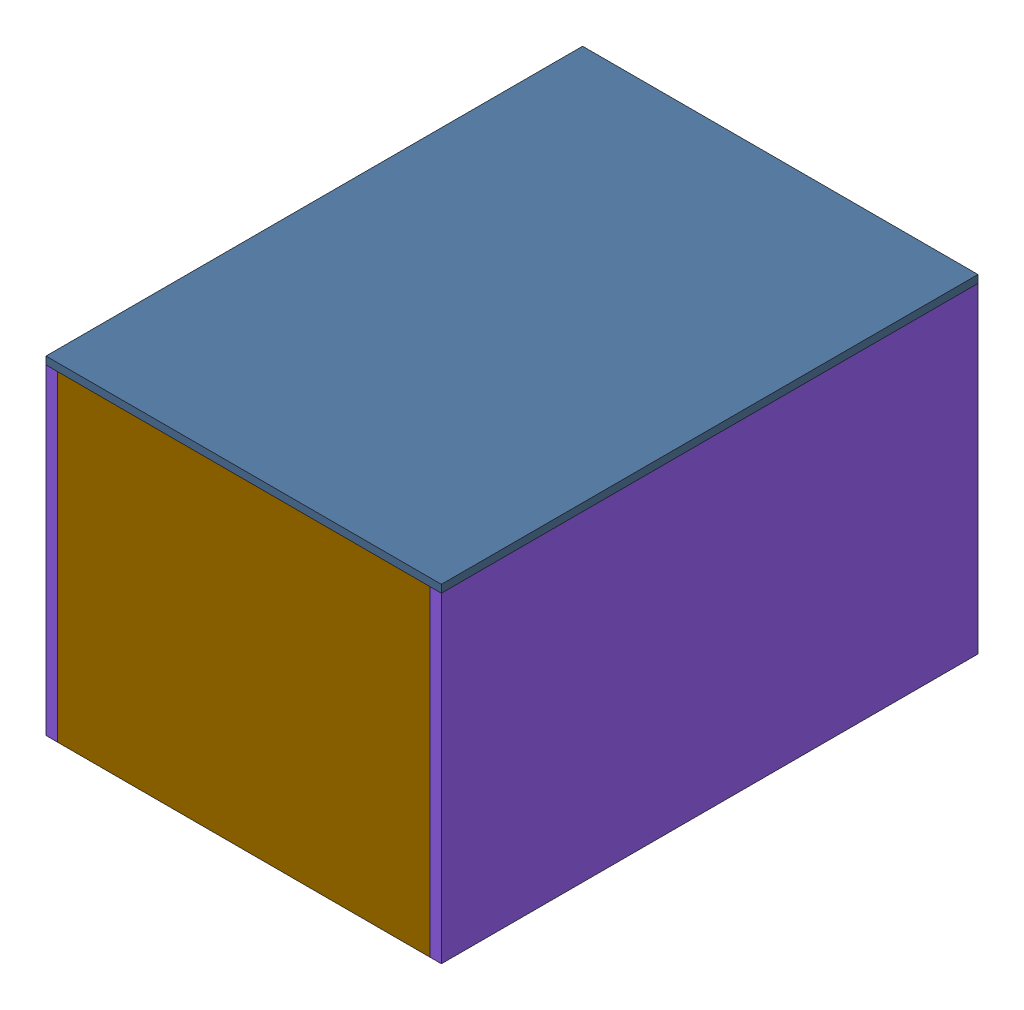
SolidWorks assembly assembly, configuration Default. Lengths in mm.
Overall size (308 256 418).
78 component instances, 28 part files, 32 mates.
Components (placement in the parent):
- base-1: base [Default] at (-177.5047 -28.3355 199.9504) size (290 9 400)
- motor_mount-1: motor_mount [Default] at (-11.0047 -19.3355 -200.0496) x (-1 0 0) z (0 1 0) size (75 48 43)
- distancer-1: distancer [Default] at (-107.8858 -19.3355 185.9504) size (9.24 40 8)
- distancer-2: distancer [Default] at (42.1142 -19.3355 185.9504) size (9.24 40 8)
- distancer-3: distancer [Default] at (-107.8858 -19.3355 -124.0496) size (9.24 40 8)
- distancer-4: distancer [Default] at (42.1142 -19.3355 -124.0496) size (9.24 40 8)
- nema_17_short-1: nema_17_short [Default] at (-53.5047 -18.8355 -197.1189) x (1 0 0) z (0 -1 0) size (42 57 42)
- Assem1-1: Assem1 [Default] at (67.4953 20.6645 194.9504) x (0 0 -1) z (1 0 0) size (330 12.5 200)
  - table-1: table [Default] at origin size (330 6 200)
  - Part1-1: Part1 [Default] at (0 6 0) x (1 0 0) z (0 1 0) size (330 95 6.5)
- Part1-1: Part1 [Default] at (-132.5047 26.6645 -135.0496) x (0 0 1) z (0 1 0) size (330 95 6.5)
- moving assembly-1: moving assembly [Default] at (160.3073 -54.8798 28.3581) x (1 0 0) z (0 1 0) size (280 330 218.5)
  - bar_and_mounts-1: bar_and_mounts [Default] at (-49.2169 -149.0461 22.6055) size (55 330 19)
    - bar_mount-1: bar_mount [Default] at (-61.595 -12.5462 12.9389) size (55 12 19)
    - bar_mount-2: bar_mount [Default] at (-61.595 295.4538 12.9389) size (55 12 19)
    - bar-1: bar [Default] at (-29.595 -17.5462 23.9389) size (8 330 8)
  - bar_and_mounts_switch-1: bar_and_mounts_switch [Default] at (-356.8295 169.2155 27.6951) x (-1 0 0) z (0 0 1) size (55 330 24.7)
    - bar_mount_switch-1: bar_mount_switch [Default] at (-82.0176 10.8078 7.8492) size (55 12 19)
    - bar-1: bar [Default] at (-50.0176 5.8078 18.8492) size (8 330 8)
    - bar_mount-1: bar_mount [Default] at (-82.0176 318.8078 7.8492) size (55 12 19)
    - switch-1: switch [Default] at (-54.8176 17.8078 26.8492) x (1 0 0) z (0 -1 0) size (12.8 5.7 10.85)
  - pusher_bearing_mount-1: pusher_bearing_mount [Default] at (-93.535 -18.6939 68.5444) size (40 50 27.5)
  - pusher_bearing_mount-2: pusher_bearing_mount [Default] at (-321.535 -18.6939 68.5444) size (40 50 27.5)
  - lm8uul-1: lm8uul [Default] at (-78.8119 -15.6939 46.5444) size (15 45 15)
  - lm8uul-2: lm8uul [Default] at (-306.8119 -15.6939 46.5444) size (15 45 15)
  - pusher_plank-1: pusher_plank [Default] at (-332.8119 -18.6939 68.5444) x (1 0 0) z (0 -1 0) size (280 6.5 50)
  - pusher_mount-1: pusher_mount [Default] at (-192.8119 -8.6939 68.5444) size (40 25 20.5)
  - socket head cap screw_din-2: socket head cap screw_din [DIN 912 M3 x 16 --- 16N] at (-89.8119 152.4077 57.5444) x (0 0 -1) z (1 0 0) size (19 5.5 5.5)
  - socket head cap screw_din-3: socket head cap screw_din [DIN 912 M3 x 16 --- 16N] at (-295.8119 152.4077 57.5444) x (0 0 -1) z (1 0 0) size (19 5.5 5.5)
  - socket head cap screw_din-4: socket head cap screw_din [DIN 912 M3 x 16 --- 16N] at (-295.8119 -155.5923 57.5444) x (0 0 -1) z (1 0 0) size (19 5.5 5.5)
  - socket head cap screw_din-5: socket head cap screw_din [DIN 912 M3 x 16 --- 16N] at (-89.8119 -155.5923 57.5444) x (0 0 -1) z (1 0 0) size (19 5.5 5.5)
  - slotted pan head screw_din-1: slotted pan head screw_din [ISO 1580 - M1.6 x 8 --- 8N] at (-311.6619 150.4077 61.2444) x (0 0 -1) z (1 0 0) size (9.03 3.2 3.2)
  - slotted pan head screw_din-4: slotted pan head screw_din [ISO 1580 - M1.6 x 8 --- 8N] at (-305.1619 150.4077 61.2444) x (0 0 -1) z (1 0 0) size (9.03 3.2 3.2)
  - slotted pan head screw_din-8: slotted pan head screw_din [ISO 1580 - M4 x 10 --- 10N] at (-207.5619 11.3061 61.1444) x (0 0 1) z (-1 0 0) size (12.47 8 8)
  - slotted pan head screw_din-9: slotted pan head screw_din [ISO 1580 - M4 x 10 --- 10N] at (-178.0619 3.8061 61.1444) x (0 0 1) z (-1 0 0) size (12.47 8 8)
  - slotted pan head screw_din-10: slotted pan head screw_din [ISO 1580 - M4 x 10 --- 10N] at (-207.5619 -3.6939 61.1444) x (0 0 1) z (-1 0 0) size (12.47 8 8)
  - prevailing torque nut style 1 insert_din-1: prevailing torque nut style 1 insert_din [DIN EN ISO 7040 - M3 - N] at (-89.8119 152.4077 41.3944) x (0.923728 0.383049 0) z (0 0 -1) size (5.5 6.35 4.5)
  - prevailing torque nut style 1 insert_din-2: prevailing torque nut style 1 insert_din [DIN EN ISO 7040 - M3 - N] at (-89.8119 -155.5923 41.3944) x (0.923728 0.383049 0) z (0 0 -1) size (5.5 6.35 4.5)
  - prevailing torque nut style 1 insert_din-3: prevailing torque nut style 1 insert_din [DIN EN ISO 7040 - M3 - N] at (-295.8119 -155.5923 41.3944) x (0.923728 0.383049 0) z (0 0 -1) size (5.5 6.35 4.5)
  - prevailing torque nut style 1 insert_din-4: prevailing torque nut style 1 insert_din [DIN EN ISO 7040 - M3 - N] at (-295.8119 152.4077 41.3944) x (-0.923728 -0.383049 0) z (0 0 -1) size (5.5 6.35 4.5)
  - toothed lock washer 1_din-1: toothed lock washer 1_din [DIN 6797-A3.2] at (-295.8119 152.4077 54.1444) x (0 0 -1) z (1 0 0) size (0.4 5.93 6)
  - toothed lock washer 1_din-2: toothed lock washer 1_din [DIN 6797-A3.2] at (-89.8119 152.4077 54.1444) x (0 0 -1) z (1 0 0) size (0.4 5.93 6)
  - toothed lock washer 1_din-3: toothed lock washer 1_din [DIN 6797-A3.2] at (-89.8119 -155.5923 54.1444) x (0 0 -1) z (1 0 0) size (0.4 5.93 6)
  - toothed lock washer 1_din-4: toothed lock washer 1_din [DIN 6797-A3.2] at (-295.8119 -155.5923 54.9444) x (0 0 1) z (-1 0 0) size (0.4 5.93 6)
  - plain washer 6902 type abc_din-2: plain washer 6902 type abc_din [DIN 6902-A3.6] at (-207.5619 -3.6939 63.5444) x (0 0 1) z (-1 0 0) size (0.8 9 9)
  - plain washer 6902 type abc_din-3: plain washer 6902 type abc_din [DIN 6902-A3.6] at (-207.5619 11.3061 63.5444) x (0 0 1) z (-1 0 0) size (0.8 9 9)
  - plain washer 6902 type abc_din-4: plain washer 6902 type abc_din [DIN 6902-A3.6] at (-178.0619 3.8061 63.5444) x (0 0 1) z (-1 0 0) size (0.8 9 9)
  - hex nut gradec_din-1: hex nut gradec_din [Hexagon Nut ISO 4034 - M8 - N] at (-192.8119 7.7061 57.0444) x (1 0 0) z (0 1 0) size (13 15.01 7.9)
  - plain washer 6902 type abc_din-5: plain washer 6902 type abc_din [DIN 6902-A3.6] at (-321.5619 6.3061 62.7444) x (0 0 1) z (-1 0 0) size (0.8 9 9)
  - plain washer 6902 type abc_din-6: plain washer 6902 type abc_din [DIN 6902-A3.6] at (-292.0619 -12.6939 63.5444) x (0 0 -1) z (1 0 0) size (0.8 9 9)
  - plain washer 6902 type abc_din-7: plain washer 6902 type abc_din [DIN 6902-A3.6] at (-292.0619 25.3061 63.5444) x (0 0 -1) z (1 0 0) size (0.8 9 9)
  - plain washer 6902 type abc_din-8: plain washer 6902 type abc_din [DIN 6902-A3.6] at (-64.0134 -12.6939 63.5444) x (0 0 -1) z (1 0 0) size (0.8 9 9)
  - plain washer 6902 type abc_din-9: plain washer 6902 type abc_din [DIN 6902-A3.6] at (-93.5619 6.3061 63.5444) x (0 0 -1) z (1 0 0) size (0.8 9 9)
  - plain washer 6902 type abc_din-10: plain washer 6902 type abc_din [DIN 6902-A3.6] at (-64.0134 25.3061 63.5444) x (0 0 -1) z (1 0 0) size (0.8 9 9)
  - toothed lock washer 1_din-5: toothed lock washer 1_din [DIN 6797-A4.3] at (-93.5619 6.3061 62.2444) x (0 0 -1) z (1 0 0) size (0.5 7.91 7.91)
  - toothed lock washer 1_din-6: toothed lock washer 1_din [DIN 6797-A4.3] at (-64.0134 -12.6939 62.2444) x (0 0 -1) z (1 0 0) size (0.5 7.91 7.91)
  - toothed lock washer 1_din-7: toothed lock washer 1_din [DIN 6797-A4.3] at (-64.0134 25.3061 62.2444) x (0 0 -1) z (1 0 0) size (0.5 7.91 7.91)
  - toothed lock washer 1_din-8: toothed lock washer 1_din [DIN 6797-A4.3] at (-292.0619 -12.6939 62.2444) x (0 0 -1) z (1 0 0) size (0.5 7.91 7.91)
  - toothed lock washer 1_din-9: toothed lock washer 1_din [DIN 6797-A4.3] at (-292.0619 25.3061 62.2444) x (0 0 -1) z (1 0 0) size (0.5 7.91 7.91)
  - toothed lock washer 1_din-11: toothed lock washer 1_din [DIN 6797-A4.3] at (-321.5619 6.3061 62.2444) x (0 0 -1) z (1 0 0) size (0.5 7.91 7.91)
  - slotted pan head screw_din-11: slotted pan head screw_din [ISO 1580 - M4 x 12 --- 12N] at (-93.5619 6.3061 59.8444) x (0 0 1) z (-1 0 0) size (14.47 8 8)
  - slotted pan head screw_din-12: slotted pan head screw_din [ISO 1580 - M4 x 12 --- 12N] at (-64.0134 25.3061 59.8444) x (0 0 1) z (-1 0 0) size (14.47 8 8)
  - slotted pan head screw_din-13: slotted pan head screw_din [ISO 1580 - M4 x 12 --- 12N] at (-64.0134 -12.6939 59.8444) x (0 0 1) z (-1 0 0) size (14.47 8 8)
  - slotted pan head screw_din-14: slotted pan head screw_din [ISO 1580 - M4 x 12 --- 12N] at (-321.5619 6.3061 59.8444) x (0 0 1) z (-1 0 0) size (14.47 8 8)
  - slotted pan head screw_din-15: slotted pan head screw_din [ISO 1580 - M4 x 12 --- 12N] at (-292.0619 25.3061 59.8444) x (0 0 1) z (-1 0 0) size (14.47 8 8)
  - slotted pan head screw_din-16: slotted pan head screw_din [ISO 1580 - M4 x 12 --- 12N] at (-292.0619 -12.6939 59.8444) x (0 0 1) z (-1 0 0) size (14.47 8 8)
  - carret-1: carret [Default] at (-332.8119 31.3061 75.0444) x (1 0 0) z (0 0 -1) size (280 6.5 120)
  - head_assembly-1: head_assembly [Default] at (-193.7359 2.3231 248.2305) x (1 0 0) z (0 1 0) size (90 120 32)
    - laserhead_base-1: laserhead_base [Default] at (-47.4396 -5.8139 28.9831) size (90 120 8)
    - mount-1: mount [Default] at (-1.9396 79.1861 36.9831) x (0 -1 0) z (-1 0 0) size (32 12 30)
    - calibration-1: calibration [Default] at (-41.9396 28.1861 36.9831) size (50 15 13)
    - calibration-2: calibration [Default] at (-41.9396 83.1861 36.9831) size (50 15 13)
    - mount_top-1: mount_top [Default] at (-31.9396 79.1861 60.9831) x (1 0 0) z (0 1 0) size (30 12 32)
- case_side-1: case_side [Default] at (-186.5047 -28.3355 208.9504) x (0 0 -1) z (1 0 0) size (418 250 9)
- case_back_side-1: case_back_side [Default] at (-177.5047 -28.3355 -209.0496) size (290 250 9)
- case_side-2: case_side [Default] at (112.4953 -28.3355 208.9504) x (0 0 -1) z (1 0 0) size (418 250 9)
- case_back_side-2: case_back_side [Default] at (112.4953 -28.3355 208.9504) x (-1 0 0) z (0 0 -1) size (290 250 9)
- case_top-1: case_top [Default] at (-186.5047 221.6645 -209.0496) x (0 0 1) z (0 1 0) size (418 308 6)
Mates (geometry in assembly coordinates):
- Coincident8: coincident: plane of base-1 through (-177.5047 -19.3355 199.9504) normal (0 1 0); plane of motor_mount-1 through (-11.0047 -19.3355 -200.0496) normal (0 -1 0)
- Coincident12: coincident: plane of base-1 through (-177.5047 -19.3355 199.9504) normal (0 1 0); plane of distancer-1 through (-107.8858 -19.3355 185.9504) normal (0 -1 0)
- Distance9: distance = 10 mm: plane of distancer-1 through (-110.1953 20.6645 189.9504) normal (0 0 1); plane of base-1 through (-177.5047 -19.3355 199.9504) normal (0 0 1)
- Distance10: distance = 65 mm: line of distancer-1 through (-112.5047 20.6645 185.9504) axis (0 -1 0); plane of base-1 through (-177.5047 -19.3355 199.9504) normal (-1 0 0)
- Coincident16: coincident: plane of motor_mount-1 through (-6.0047 23.6645 -157.1189) normal (0 0 -1); plane of nema_17_short-1 through (-14.5047 20.1645 -157.1189) normal (0 0 1)
- Concentric3: concentric: cylinder of motor_mount-1 through (-32.5047 2.1645 -200.0496) axis (0 0 1) radius 11.25; cylinder of nema_17_short-1 through (-32.5047 2.1645 -155.1189) axis (0 0 -1) radius 11
- Distance16: distance = 107.5 mm: plane of motor_mount-1 through (-70.0047 -14.3355 -200.0496) normal (-1 0 0); plane of base-1 through (-177.5047 -19.3355 199.9504) normal (-1 0 0)
- Distance20: distance = 0 mm: plane of motor_mount-1 through (-54.0047 -14.3355 -200.0496) normal (0 0 -1); line of base-1 through (112.4953 -19.3355 -200.0496) axis (-1 0 0)
- Coincident47: coincident: plane of distancer-1 through (-107.8858 20.6645 185.9504) normal (0 1 0); plane of Assem1-1/table-1 through (67.4953 20.6645 194.9504) normal (0 -1 0)
- Distance23: distance = 5 mm: plane of base-1 through (-177.5047 -19.3355 199.9504) normal (0 0 1); plane of Assem1-1/table-1 through (67.4953 26.6645 194.9504) normal (0 0 1)
- Distance24: distance = 45 mm: plane of Assem1-1/table-1 through (67.4953 26.6645 194.9504) normal (1 0 0); plane of base-1 through (112.4953 -19.3355 199.9504) normal (1 0 0)
- Coincident48: coincident: plane of Assem1-1/table-1 through (67.4953 26.6645 194.9504) normal (1 0 0); plane of Part1-1 through (67.4953 33.1645 -135.0496) normal (1 0 0)
- Coincident49: coincident: plane of Assem1-1/table-1 through (67.4953 26.6645 194.9504) normal (0 1 0); plane of Part1-1 through (-132.5047 26.6645 -135.0496) normal (0 -1 0)
- Coincident51: coincident: plane of Assem1-1/table-1 through (67.4953 26.6645 194.9504) normal (0 0 1); plane of Part1-1 through (67.4953 33.1645 194.9504) normal (0 0 1)
- Coincident52: coincident: plane of base-1 through (-177.5047 -19.3355 199.9504) normal (0 1 0); plane of moving assembly-1/bar_and_mounts_switch-1/bar_mount_switch-1 through (-114.5047 -19.3355 -130.0496) normal (0 -1 0)
- Distance25: distance = 8 mm: plane of moving assembly-1/bar_and_mounts_switch-1/bar_mount_switch-1 through (-169.5047 -13.3355 -130.0496) normal (-1 0 0); plane of base-1 through (-177.5047 -19.3355 199.9504) normal (-1 0 0)
- Distance26: distance = 5 mm: plane of moving assembly-1/bar_and_mounts-1/bar_mount-1 through (49.4953 -13.3355 189.9504) normal (0 0 1); plane of Assem1-1/table-1 through (67.4953 26.6645 194.9504) normal (0 0 1)
- Coincident53: coincident: plane of base-1 through (-177.5047 -19.3355 199.9504) normal (-1 0 0); plane of case_side-1 through (-177.5047 -28.3355 208.9504) normal (1 0 0)
- Coincident54: coincident: plane of base-1 through (-177.5047 -28.3355 199.9504) normal (0 -1 0); plane of case_side-1 through (-177.5047 -28.3355 208.9504) normal (0 -1 0)
- Coincident55: coincident: plane of base-1 through (-177.5047 -28.3355 199.9504) normal (0 -1 0); plane of case_back_side-1 through (-177.5047 -28.3355 -200.0496) normal (0 -1 0)
- Coincident56: coincident: plane of base-1 through (-177.5047 -19.3355 -200.0496) normal (0 0 -1); plane of case_back_side-1 through (-177.5047 -28.3355 -200.0496) normal (0 0 1)
- Coincident57: coincident: plane of case_side-1 through (-177.5047 -28.3355 208.9504) normal (1 0 0); plane of case_back_side-1 through (-177.5047 -28.3355 -200.0496) normal (-1 0 0)
- Coincident58: coincident: plane of case_side-1 through (-177.5047 -28.3355 -209.0496) normal (0 0 -1); plane of case_back_side-1 through (-177.5047 -28.3355 -209.0496) normal (0 0 -1)
- Coincident59: coincident: plane of base-1 through (-177.5047 -28.3355 199.9504) normal (0 -1 0); plane of case_side-2 through (121.4953 -28.3355 208.9504) normal (0 -1 0)
- Coincident60: coincident: plane of case_back_side-1 through (-177.5047 -28.3355 -209.0496) normal (0 0 -1); plane of case_side-2 through (121.4953 -28.3355 -209.0496) normal (0 0 -1)
- Coincident61: coincident: plane of base-1 through (112.4953 -19.3355 199.9504) normal (1 0 0); plane of case_side-2 through (112.4953 -28.3355 208.9504) normal (-1 0 0)
- Coincident62: coincident: plane of base-1 through (-177.5047 -19.3355 199.9504) normal (0 0 1); plane of case_back_side-2 through (112.4953 -28.3355 199.9504) normal (0 0 -1)
- Coincident63: coincident: plane of base-1 through (-177.5047 -28.3355 199.9504) normal (0 -1 0); plane of case_back_side-2 through (112.4953 -28.3355 199.9504) normal (0 -1 0)
- Coincident64: coincident: plane of case_side-2 through (112.4953 -28.3355 208.9504) normal (-1 0 0); plane of case_back_side-2 through (112.4953 -28.3355 199.9504) normal (1 0 0)
- Coincident65: coincident: plane of case_side-2 through (121.4953 221.6645 208.9504) normal (0 1 0); plane of case_top-1 through (-186.5047 221.6645 -209.0496) normal (0 -1 0)
- Coincident66: coincident: plane of case_side-2 through (121.4953 -28.3355 208.9504) normal (1 0 0); plane of case_top-1 through (121.4953 227.6645 -209.0496) normal (1 0 0)
- Coincident67: coincident: plane of case_back_side-2 through (112.4953 -28.3355 208.9504) normal (0 0 1); plane of case_top-1 through (-186.5047 227.6645 208.9504) normal (0 0 1)
